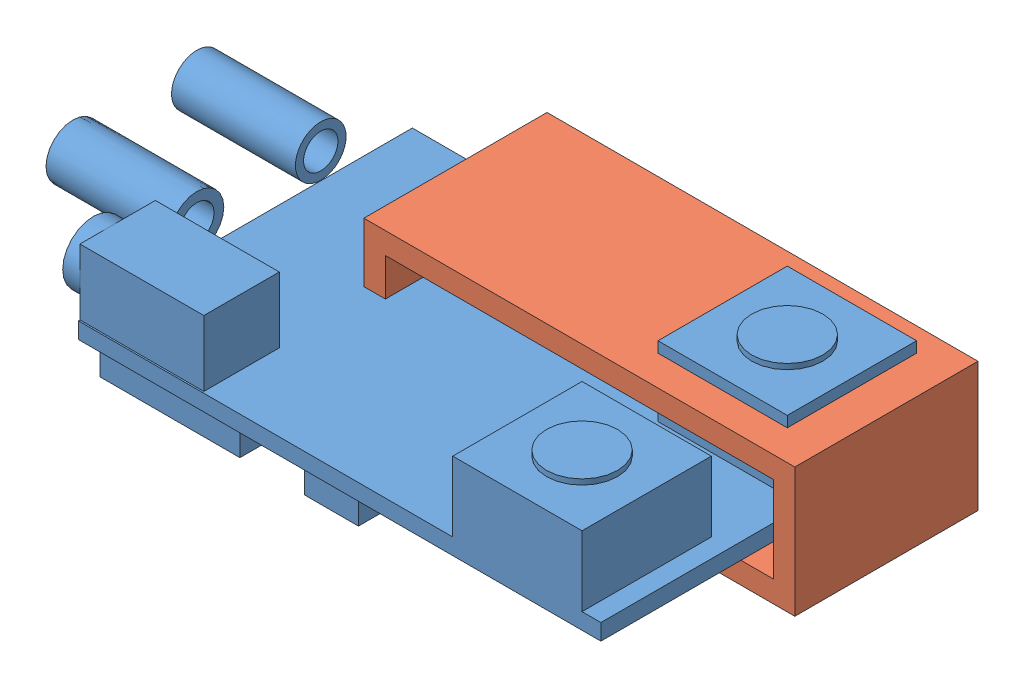
SolidWorks assembly Baugruppe1, configuration Standard. Lengths in mm.
Overall size (62 13.5 33).
2 component instances, 2 part files, 3 mates.
Components (placement in the parent):
- PTT-1: PTT [Standard] at (-33.1783 1.4396 60) size (60 11.5 31)
- Housing-Left-1: Housing-Left [Standard] at (17.3217 -3.5604 27) size (40 12 17)
Mates (geometry in assembly coordinates):
- Deckungsgleich1: coincident: plane of PTT-1 through (-33.1783 2.9396 29) normal (0 0 -1); plane of Housing-Left-1 through (17.3217 -3.5604 29) normal (0 0 1)
- Deckungsgleich2: coincident: plane of PTT-1 through (15.3217 2.9396 60) normal (1 0 0); plane of Housing-Left-1 through (15.3217 6.4396 44) normal (-1 0 0)
- Deckungsgleich3: coincident anti-aligned: plane of PTT-1 through (-33.1783 -1.5604 60) normal (0 -1 0); plane of Housing-Left-1 through (-20.6783 -1.5604 44) normal (0 1 0)
